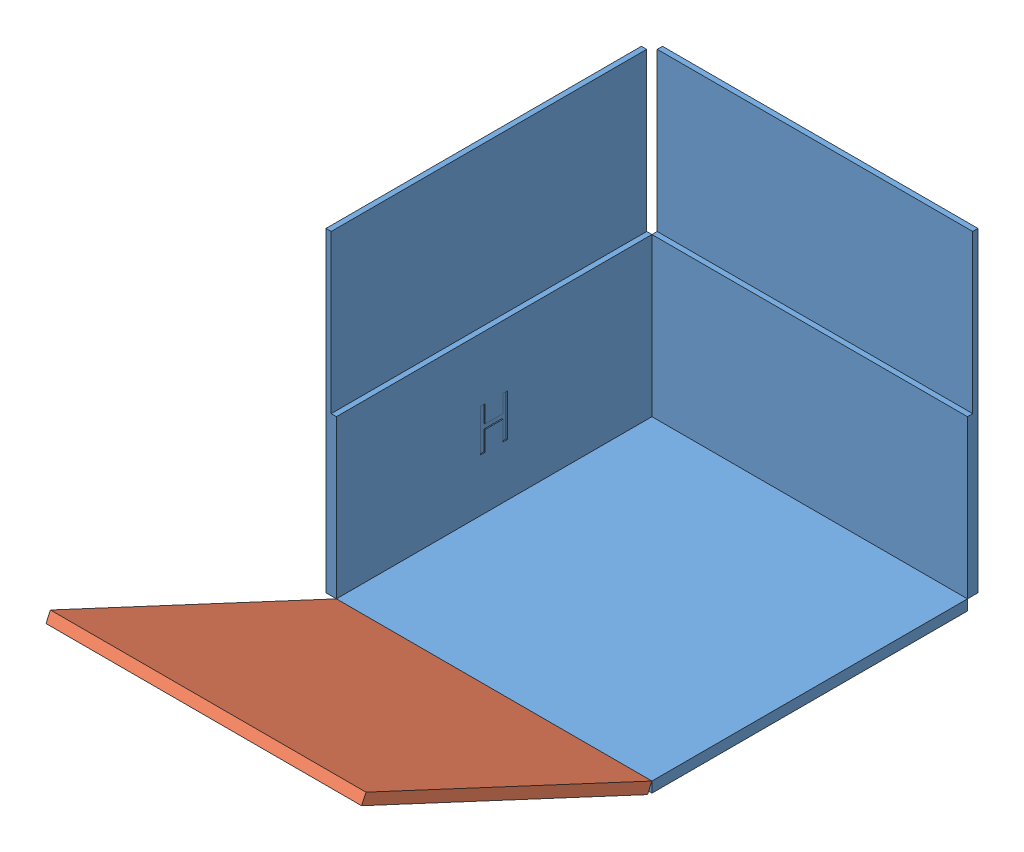
SolidWorks assembly maze, configuration Default. Lengths in mm.
Overall size (310 310 586.12).
2 component instances, 2 part files, 3 mates.
Components (placement in the parent):
- maze_cell-1: maze_cell [Default] at origin size (310 310 310)
- maze_slope-1: maze_slope [Default] at (0 -9.0631 4.2262) x (0 0.422618 0.906308) z (-1 0 0) size (300 10 300)
Mates (geometry in assembly coordinates):
- Coincident4: coincident anti-aligned: line of maze_cell-1 through (0 300 0) axis (0 0 1); line of maze_slope-1 through (300 0 0) axis (-1 0 0)
- Coincident5: coincident aligned: plane of maze_cell-1 through (300 -10 0) normal (1 0 0); plane of maze_slope-1 through (300 0 0) normal (1 0 0)
- Angle2: planar angle = 3.577925 rad anti-aligned: plane of maze_slope-1 through (0 0 0) normal (0 0.906308 -0.422618); plane of maze_cell-1 through (0 0 0) normal (0 1 0)
